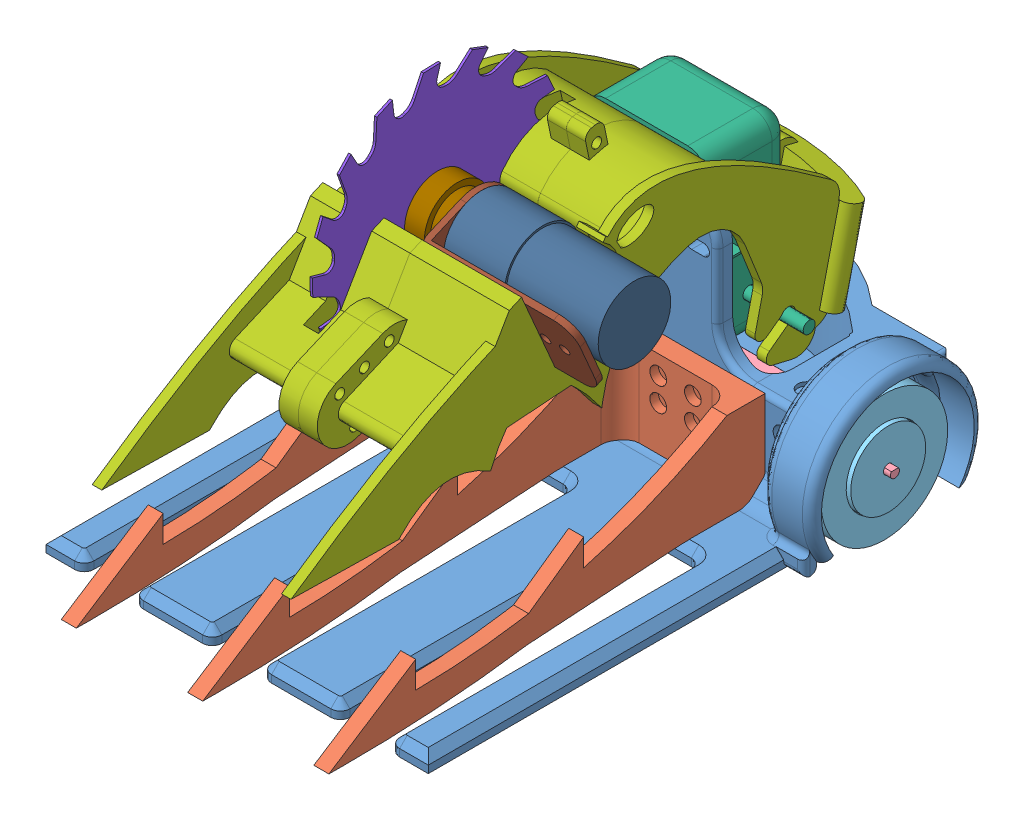
SolidWorks assembly BattleBot_Alligator, configuration Default. Lengths in mm.
Overall size (148.04 137.04 203.29).
14 component instances, 11 part files, 27 mates.
Components (placement in the parent):
- Body_V2-1: Body_V2 [Default] at origin size (148.04 78.83 188.17)
- BottomSpikesCombo2-4: BottomSpikesCombo2 [Default] at (-39.45 -15.3303 13.9803) x (0 0 1) z (-1 0 0) size (144.96 37.48 88.9)
- Motor_Mount_2-3: Motor_Mount_2 [Default] at (52.3875 -24.8553 -0.5447) x (0 -1 0) z (-1 0 0) size (25.4 19.05 4.76)
- fingertech_22to1_Motor-2: fingertech_22to1_Motor [Default] at (34.825 -24.8553 -0.5447) x (0 0 -1) z (1 0 0) size (16 16 70.2)
- 2in_Wheel-4: 2in_Wheel [Default] at (63.1825 -24.8553 -0.5447) x (0 0.894725 -0.446617) z (-1 0 0) size (42.04 42.04 15.24)
- fingertech_22to1_Motor-3: fingertech_22to1_Motor [Default] at (-34.825 -24.8553 -0.5447) x (0 0 1) z (-1 0 0) size (16 16 70.2)
- Motor_Mount_2-5: Motor_Mount_2 [Default] at (-52.3875 -24.8553 -0.5447) x (0 1 0) z (1 0 0) size (25.4 19.05 4.76)
- 2in_Wheel-5: 2in_Wheel [Default] at (-63.1825 -24.8553 -0.5447) x (0 0.894725 -0.446617) z (-1 0 0) size (42.04 42.04 15.24)
- HeadGearBox-1: HeadGearBox [Default] at (0 14.3197 8.9003) x (-1 0 0) z (0 0 -1) size (80 60 28)
- TopSpikeCombo-1: TopSpikeCombo [Default] at (33.02 14.2165 68.3613) x (0 0.228683 0.973501) z (-1 0 0) size (187.96 87.2 73.1)
- Blade-1: Blade [Default] at (-15.24 39.5855 63.9265) x (0 0.032574 -0.999469) z (1 0 0) size (83.18 83.18 0.81)
- Blade_Hub-1: Blade_Hub [Default] at (-14.4272 39.5855 63.9265) x (0 0.112881 -0.993609) z (1 0 0) size (21.97 21.97 12.06)
- 25D_Motor-1: 25D_Motor [Default] at (50.9778 39.5855 63.9265) x (0 0.235284 0.971927) z (-1 0 0) size (25.4 25.4 62.87)
- 25DMotor_Mount-1: 25DMotor_Mount [Default] at (-1.8542 39.5855 63.9265) x (0 0.917952 0.396692) z (-1 0 0) size (25.4 27.43 50.8)
Mates (geometry in assembly coordinates):
- Coincident1: coordinate: point of Body_V2-1; point of assembly
- Coincident15: coincident anti-aligned: plane of Body_V2-1 through (-63.5 -8.9803 13.9803) normal (0 0 1); plane of BottomSpikesCombo2-4 through (-44.45 -21.6803 13.9803) normal (0 0 -1)
- Coincident16: coincident aligned: plane of Body_V2-1 through (-63.5 -8.9803 13.9803) normal (0 1 0); plane of BottomSpikesCombo2-4 through (-44.45 -8.9803 13.9803) normal (0 1 0)
- Parallel2: parallel anti-aligned: plane of Body_V2-1 through (-62.23 -12.1553 -29.1197) normal (0 -1 0); plane of fingertech_22to1_Motor-2 through (34.825 -18.8553 -5.2905) normal (0 1 0)
- Coincident29: coincident anti-aligned: axis of fingertech_22to1_Motor-2 through (73.025 -24.8553 -0.5447) axis (-1 0 0); axis of 2in_Wheel-4 through (56.8325 -24.8553 -0.5447) axis (1 0 0)
- Coincident30: coincident anti-aligned: plane of Body_V2-1 through (35.56 -22.4423 8.9003) normal (0 0 -1); plane of HeadGearBox-1 through (0 14.3197 8.9003) normal (0 0 1)
- Distance6: distance = 3.175 mm anti-aligned: plane of HeadGearBox-1 through (20 -15.6803 -19.0997) normal (0 -1 0); plane of fingertech_22to1_Motor-3 through (-34.825 -18.8553 4.201) normal (0 1 0)
- Coincident32: coincident anti-aligned: plane of Body_V2-1 through (0 0 0) normal (1 0 0); plane of HeadGearBox-1 through (0 14.3197 8.9003) normal (-1 0 0)
- Coincident33: coincident aligned: axis of HeadGearBox-1 through (20 -1.6803 -5.0997) axis (1 0 0); axis of TopSpikeCombo-1 through (29.845 -1.6803 -5.0997) axis (1 0 0)
- Coincident34: coincident anti-aligned: plane of Body_V2-1 through (0 0 0) normal (1 0 0); plane of TopSpikeCombo-1 through (0 14.2165 68.3613) normal (-1 0 0)
- LimitAngle3: limit planar angle = 3.122303 rad aligned: plane of TopSpikeCombo-1 through (29.845 -2.6582 68.6868) normal (0 -0.999814 0.019288); plane of Body_V2-1 through (-63.5 -38.3605 17.9605) normal (0 1 0)
- Coincident37: coincident aligned: axis of Motor_Mount_2-3 through (50.125 -24.8553 -0.5447) axis (-1 0 0); axis of fingertech_22to1_Motor-2 through (73.025 -24.8553 -0.5447) axis (-1 0 0)
- Coincident38: coincident anti-aligned: plane of Body_V2-1 through (-63.5 -8.9803 8.9803) normal (0 0 -1); plane of Motor_Mount_2-3 through (47.625 -12.1553 8.9803) normal (0 0 1)
- Coincident39: coincident anti-aligned: plane of Body_V2-1 through (-62.23 -12.1553 -29.1197) normal (0 -1 0); plane of Motor_Mount_2-3 through (47.625 -12.1553 -10.0697) normal (0 1 0)
- Distance7: distance = 3.175 mm anti-aligned: plane of 2in_Wheel-4 through (55.5625 -24.8553 -0.5447) normal (-1 0 0); plane of Motor_Mount_2-3 through (52.3875 -37.5553 -10.0697) normal (1 0 0)
- Coincident40: coincident anti-aligned: plane of Motor_Mount_2-3 through (47.625 -37.5553 -10.0697) normal (-1 0 0); plane of fingertech_22to1_Motor-2 through (47.625 -24.8553 -0.5447) normal (1 0 0)
- Distance8: distance = 52.3875 mm anti-aligned: plane of Body_V2-1 through (0 0 0) normal (1 0 0); plane of Motor_Mount_2-3 through (52.3875 -24.8553 -0.5447) normal (-1 0 0)
- Coincident41: coincident anti-aligned: plane of Body_V2-1 through (0 0 0) normal (1 0 0); plane of BottomSpikesCombo2-4 through (0 -15.3303 13.9803) normal (-1 0 0)
- Distance10: distance = 15.24 mm anti-aligned: plane of TopSpikeCombo-1 through (0 14.2165 68.3613) normal (-1 0 0); plane of Blade-1 through (-15.24 39.5855 63.9265) normal (1 0 0)
- Coincident43: coincident anti-aligned: plane of Blade-1 through (-14.4272 77.0184 76.1238) normal (1 0 0); plane of Blade_Hub-1 through (-14.4272 39.5855 63.9265) normal (-1 0 0)
- Coincident44: coincident aligned: axis of Blade-1 through (-14.4272 39.5855 63.9265) axis (-1 0 0); axis of Blade_Hub-1 through (-7.8232 39.5855 63.9265) axis (-1 0 0)
- Coincident45: coincident anti-aligned: axis of Blade_Hub-1 through (-2.3622 39.5855 63.9265) axis (-1 0 0); axis of 25D_Motor-1 through (-11.8872 39.5855 63.9265) axis (1 0 0)
- Coincident47: coincident anti-aligned: plane of Blade_Hub-1 through (-2.3622 39.5855 63.9265) normal (1 0 0); plane of 25D_Motor-1 through (-2.3622 39.5855 63.9265) normal (-1 0 0)
- Coincident49: coincident anti-aligned: axis of 25D_Motor-1 through (-2.3622 39.5855 63.9265) axis (1 0 0); axis of 25DMotor_Mount-1 through (0.1778 39.5855 63.9265) axis (-1 0 0)
- Coincident52: coincident anti-aligned: plane of 25D_Motor-1 through (0.1778 39.5855 63.9265) normal (-1 0 0); plane of 25DMotor_Mount-1 through (0.1778 39.5855 63.9265) normal (1 0 0)
- Coincident54: coincident anti-aligned: plane of TopSpikeCombo-1 through (71.7689 13.9796 68.9097) normal (0 0.396692 -0.917952); plane of 25DMotor_Mount-1 through (0.1778 22.0835 72.4118) normal (0 -0.396692 0.917952)
- Distance13: distance = 2.54 mm aligned: plane of 25DMotor_Mount-1 through (0.1778 51.2435 68.9645) normal (0 0.917952 0.396692); plane of TopSpikeCombo-1 through (71.7689 47.968 82.947) normal (0 0.917952 0.396692)
